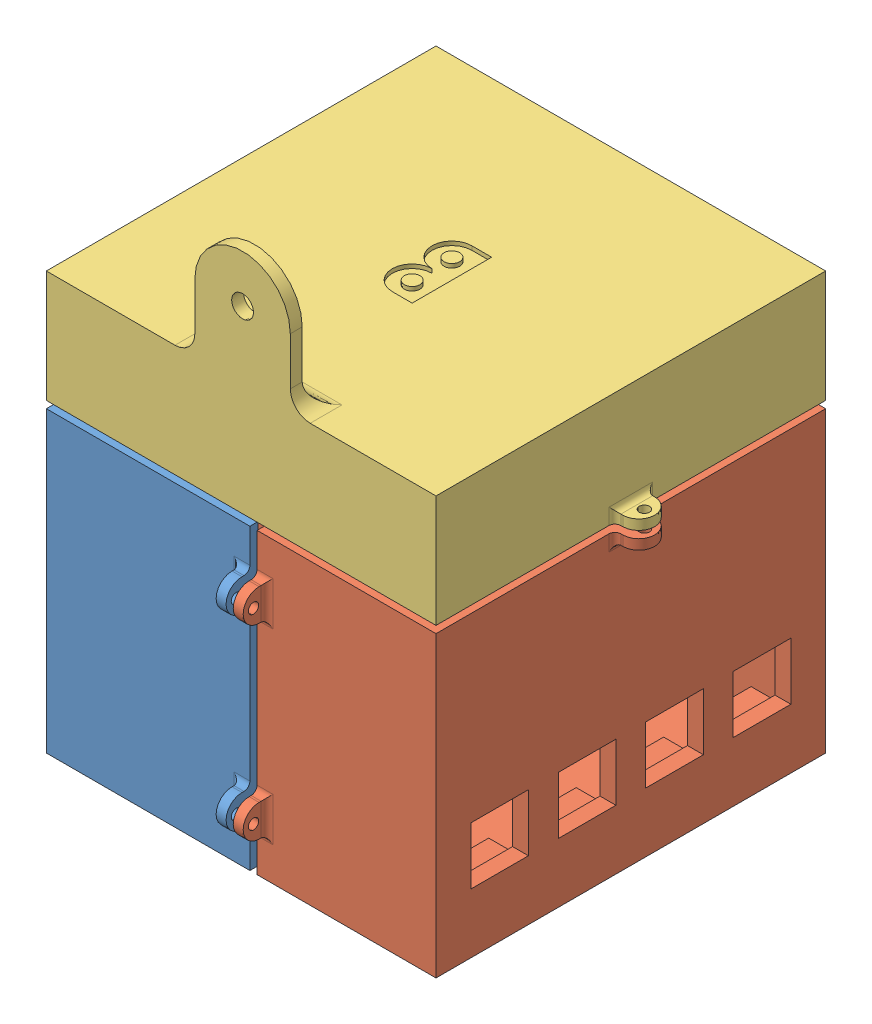
SolidWorks assembly boxF, configuration Default. Lengths in mm.
Overall size (110 134 110).
3 component instances, 3 part files, 2 mates.
Components (placement in the parent):
- 2lx-2: 2lx [Default] at (15.7384 30.3159 116.1996) size (57.2 80 110)
- rx0-2: rx0 [Default] at (63.0936 -9.1277 229.4288) x (-1 0 0) z (0 0 -1) size (56 80 110)
- log-2: log [Default] at (38.2384 135.3159 116.1996) x (-1 0 0) z (0 0 1) size (110 57.2 98)
Mates (geometry in assembly coordinates):
- Coincident1: coincident: point of 2lx-2; point of rx0-2
- Coincident2: coincident: point of 2lx-2; point of log-2
